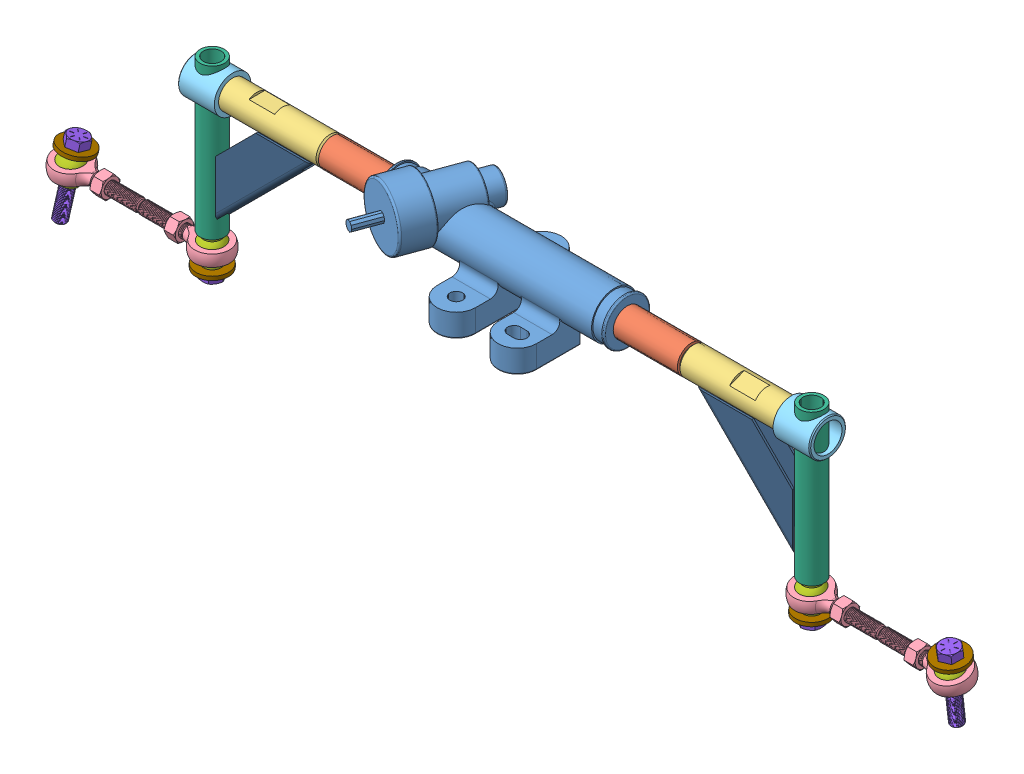
SolidWorks assembly steering assembly, configuration Default. Lengths in mm.
Overall size (719.66 185.7 106.9).
27 component instances, 11 part files, 77 mates.
Components (placement in the parent):
- prebuilt housing-1: prebuilt housing [Default] at (-22.0598 82.7728 134.0833) size (180 70.59 106.9)
- prebuilt rack-1: prebuilt rack [Default] at (207.9402 82.7728 134.0833) x (0 0.567124 0.823632) z (0 -0.823632 0.567124) size (22 312 22)
- extender-1: extender [Default] at (291.9402 82.7728 134.0833) x (0 0.924347 0.381554) z (0 -0.381554 0.924347) size (21.8 84.01 21.8)
- extender-2: extender [Default] at (-156.0598 82.7728 134.0833) x (0 -0.999985 -0.005515) z (0 -0.005515 0.999985) size (21.8 84.01 21.8)
- 3-8-24 swivel-2: 3-8-24 swivel [Default] at (-221.5288 30.3182 118.8367) x (0 -0.06645 0.99779) z (0 -0.99779 -0.06645) size (28.57 68.61 16.22)
- 3-8-24 swivel-3: 3-8-24 swivel [Default] at (-219.9278 28.9769 153.7657) x (0 0.010267 -0.999947) z (0 -0.999947 -0.010267) size (28.57 68.61 16.22)
- 3-8-24 swivel-4: 3-8-24 swivel [Default] at (355.8083 30.5302 119.6738) x (0 -0.080712 0.996738) z (0 -0.996738 -0.080712) size (28.57 68.61 16.22)
- 3-8-24 swivel-5: 3-8-24 swivel [Default] at (357.4092 22.1199 167.5981) x (0 0.263498 -0.96466) z (0 -0.96466 -0.263498) size (28.57 68.61 16.22)
- RackVertAdapt-1: RackVertAdapt [Default] at (-178.6598 82.7728 134.0833) size (28.57 28.57 28.57)
- RackVertAdapt-2: RackVertAdapt [Default] at (314.5402 82.7728 134.0833) x (-1 0 0) z (0 0 -1) size (28.57 28.57 28.57)
- Rackvertical-1: Rackvertical [Default] at (-165.9598 -16.996 134.0833) size (19.05 117.47 19.05)
- Rackvertical-2: Rackvertical [Default] at (301.8402 -16.996 134.0833) x (-0.951218 0 -0.308519) z (0.308519 0 -0.951218) size (19.05 117.47 19.05)
- BallSuper-Swivel  Joint Rod End6960T231_-1: BallSuper-Swivel  Joint Rod End6960T231_ [6960T231] at (-156.8566 -28.1085 117.349) x (0.878438 0 0.477856) z (0 -1 0) size (20.64 20.64 22.23)
- BallSuper-Swivel  Joint Rod End6960T231_-2: BallSuper-Swivel  Joint Rod End6960T231_ [6960T231] at (319.6786 -28.1085 127.398) x (0.350934 0 0.9364) z (0 -1 0) size (20.64 20.64 22.23)
- BallSuper-Swivel  Joint Rod End6960T231_-4: BallSuper-Swivel  Joint Rod End6960T231_ [6960T231] at (393.3175 -26.7315 128.1798) x (0.316739 0.120745 -0.940796) z (-0.030588 -0.990048 -0.137364) size (20.64 20.64 22.23)
- 91257A659_Zinc Yellow-Chromate Plated Hex Head Screw-2: 91257A659_Zinc Yellow-Chromate Plated Hex Head Screw [91257A659] at (411.1286 -36.1556 132.9668) x (-0.030588 -0.990048 -0.137364) z (-0.987463 0.051224 -0.14931) size (57.6 16.5 14.29)
- 91257A659_Zinc Yellow-Chromate Plated Hex Head Screw-3: 91257A659_Zinc Yellow-Chromate Plated Hex Head Screw [91257A659] at (301.8402 -19.9805 134.0833) x (0 1 0) z (-0.546944 0 0.837169) size (57.6 16.5 14.29)
- 91257A659_Zinc Yellow-Chromate Plated Hex Head Screw-4: 91257A659_Zinc Yellow-Chromate Plated Hex Head Screw [91257A659] at (-165.9598 -19.9805 134.0833) x (0 1 0) z (0 0 1) size (57.6 16.5 14.29)
- 3-8 98029A046_Black-Oxide Steel Oversized Washer-2: 3-8 98029A046_Black-Oxide Steel Oversized Washer [98029A046] at (-165.9598 -40.7133 134.0833) x (0.990245 0 -0.139337) z (0 1 0) size (25.4 25.4 2.98)
- 3-8 98029A046_Black-Oxide Steel Oversized Washer-3: 3-8 98029A046_Black-Oxide Steel Oversized Washer [98029A046] at (301.8402 -40.7133 134.0833) x (1 0 0) z (0 1 0) size (25.4 25.4 2.98)
- 3-8 98029A046_Black-Oxide Steel Oversized Washer-4: 3-8 98029A046_Black-Oxide Steel Oversized Washer [98029A046] at (411.7628 -15.6292 135.8147) x (-0.655719 -0.083846 0.750335) z (0.030588 0.990048 0.137364) size (25.4 25.4 2.98)
- BallSuper-Swivel  Joint Rod End6960T231_-5: BallSuper-Swivel  Joint Rod End6960T231_ [6960T231] at (-293.2915 -25.3278 140.2896) x (-0.34361 -0.120036 -0.93141) z (-0.096851 -0.98198 0.162283) size (20.64 20.64 22.23)
- 3-8 98029A046_Black-Oxide Steel Oversized Washer-5: 3-8 98029A046_Black-Oxide Steel Oversized Washer [98029A046] at (-274.276 -15.7309 132.0377) x (0.995265 -0.096906 0.007598) z (-0.096851 -0.98198 0.162283) size (25.4 25.4 2.98)
- 91257A659_Zinc Yellow-Chromate Plated Hex Head Screw-5: 91257A659_Zinc Yellow-Chromate Plated Hex Head Screw [91257A659] at (-276.284 -36.09 135.4023) x (-0.096851 -0.98198 0.162283) z (-0.622443 0.186989 0.76) size (57.6 16.5 14.29)
- Part1^steering assembly-1: Part1^steering assembly [Default] at origin (virtual)
- GussetSteering-2: GussetSteering [Default] at (130.9725 -5.6175 134.0833) size (74.76 74.76 14.22)
- GussetSteering-3: GussetSteering [Default] at (-78.221 -90.1796 134.0833) x (0 1 0) z (0 0 1) size (74.76 74.76 14.22)
Mates (geometry in assembly coordinates):
- Concentric1: concentric anti-aligned: cylinder of prebuilt housing-1 through (157.9402 82.7728 134.0833) axis (-1 0 0) radius 11; cylinder of prebuilt rack-1 through (-72.0598 82.7728 134.0833) axis (1 0 0) radius 11
- Concentric5: concentric anti-aligned: circle of prebuilt ball joint-1; circle of prebuilt ball joint end-1
- Concentric6: concentric: sphere of prebuilt ball joint end-1; sphere of ball end joint conection piece-1
- Concentric8: concentric anti-aligned: circle of prebuilt rack-1; cylinder of extender-1 through (177.1104 82.7728 134.0833) axis (1 0 0) radius 10.9
- Coincident3: coincident anti-aligned: plane of prebuilt rack-1 through (-72.0598 95.1403 107.9625) normal (-1 0 0); plane of extender-2 through (-72.0598 99.5437 110.5464) normal (1 0 0)
- Coincident8: coincident anti-aligned: plane of prebuilt rack-1 through (207.9402 95.1403 107.9625) normal (1 0 0); circle of extender-1
- Coincident4: coincident anti-aligned: plane of prebuilt rack-1 through (207.9402 95.1403 107.9625) normal (1 0 0); plane of extender-1 through (207.9402 76.4066 105.8925) normal (-1 0 0)
- Concentric10: concentric anti-aligned: circle of extender-2; circle of rackBallEnd-2
- Coincident5: coincident anti-aligned: plane of extender-2 through (-156.0598 82.7728 134.0833) normal (-1 0 0); plane of rackBallEnd-2 through (-137.0598 82.7728 134.0833) normal (1 0 0)
- Concentric11: concentric anti-aligned: circle of extender-1; circle of rackBallEnd-1
- Coincident6: coincident anti-aligned: plane of extender-1 through (291.9402 82.7728 134.0833) normal (1 0 0); plane of rackBallEnd-1 through (272.9402 82.7728 134.0833) normal (-1 0 0)
- Concentric12: concentric: sphere of prebuilt ball joint-1; sphere of rackBallEnd-1
- Concentric13: concentric: sphere of prebuilt ball joint-2; sphere of rackBallEnd-2
- Coincident7: coincident: point of prebuilt housing-1; point of prebuilt rack-1
- Parallel3: parallel anti-aligned: plane of prebuilt ball joint-1 through (357.8661 84.527 123.1579) normal (0.9847 0.027626 -0.172054); plane of prebuilt ball joint end-1 through (367.9391 84.8096 121.3978) normal (-0.9847 -0.027626 0.172054)
- Lock1: lock: unknown of prebuilt ball joint-1; unknown of prebuilt ball joint end-1
- Concentric14: concentric aligned: cylinder of extender-2 through (-41.2299 82.7728 134.0833) axis (-1 0 0) radius 10.9; cylinder of RackVertAdapt-1 through (-150.0848 82.7728 134.0833) axis (-1 0 0) radius 10.9093
- Concentric15: concentric aligned: cylinder of extender-1 through (177.1104 82.7728 134.0833) axis (1 0 0) radius 10.9; cylinder of RackVertAdapt-2 through (285.9652 82.7728 134.0833) axis (1 0 0) radius 10.9093
- Concentric16: concentric anti-aligned: cylinder of RackVertAdapt-2 through (301.8402 63.7228 134.0833) axis (0 1 0) radius 9.5885
- Concentric17: concentric anti-aligned: cylinder of RackVertAdapt-1 through (-165.9598 63.7228 134.0833) axis (0 1 0) radius 9.5885
- Coincident11: coincident aligned: line of Rackvertical-2 through (301.8402 100.479 134.0833) axis (0 -1 0)
- Coincident12: coincident: point of Rackvertical-2; point of assembly
- Coincident13: coincident aligned: line of Rackvertical-1 through (-165.9598 100.479 134.0833) axis (0 -1 0)
- Coincident14: coincident: point of Rackvertical-1; point of assembly
- Concentric19: concentric anti-aligned: circle of Rackvertical-1; circle of BallSuper-Swivel  Joint Rod End6960T231_-1
- Coincident15: coincident aligned: plane of Rackvertical-1 through (-175.4848 -16.996 134.0833) normal (0 -1 0); circle of BallSuper-Swivel  Joint Rod End6960T231_-1
- Concentric22: concentric anti-aligned: circle of Rackvertical-2; circle of BallSuper-Swivel  Joint Rod End6960T231_-2
- Coincident16: coincident aligned: plane of Rackvertical-2 through (310.9006 -16.996 137.0219) normal (0 -1 0); circle of BallSuper-Swivel  Joint Rod End6960T231_-2
- Concentric23: concentric anti-aligned: circle of BallSuper-Swivel  Joint Rod End6960T231_-1; circle of 3-8 98029A046_Black-Oxide Steel Oversized Washer-2
- Coincident17: coincident anti-aligned: circle of BallSuper-Swivel  Joint Rod End6960T231_-1; plane of 3-8 98029A046_Black-Oxide Steel Oversized Washer-2 through (-165.9598 -39.221 134.0833) normal (0 1 0)
- Concentric25: concentric anti-aligned: circle of BallSuper-Swivel  Joint Rod End6960T231_-2; circle of 3-8 98029A046_Black-Oxide Steel Oversized Washer-3
- Coincident19: coincident anti-aligned: circle of BallSuper-Swivel  Joint Rod End6960T231_-2; plane of 3-8 98029A046_Black-Oxide Steel Oversized Washer-3 through (301.8402 -39.221 134.0833) normal (0 1 0)
- Coincident21: coincident aligned: plane of 91257A659_Zinc Yellow-Chromate Plated Hex Head Screw-3 through (294.4801 -42.2055 137.808) normal (0 1 0); circle of 3-8 98029A046_Black-Oxide Steel Oversized Washer-3
- Coincident22: coincident: point of 3-8-24 swivel-2; point of ?
- Concentric27: concentric anti-aligned: cylinder of BallSuper-Swivel  Joint Rod End6960T231_-3 through (-265.1781 -28.1085 134.0833) axis (-1 0 0) radius 4.7625; cylinder of 91257A659_Zinc Yellow-Chromate Plated Hex Head Screw-1 through (-289.5938 -28.1085 134.0833) axis (1 0 0) radius 4.7625
- Concentric28: concentric anti-aligned: circle of 91257A659_Zinc Yellow-Chromate Plated Hex Head Screw-1; circle of 3-8 98029A046_Black-Oxide Steel Oversized Washer-1
- Coincident23: coincident anti-aligned: plane of BallSuper-Swivel  Joint Rod End6960T231_-3 through (-286.6093 -28.1085 134.0833) normal (-1 0 0); plane of 3-8 98029A046_Black-Oxide Steel Oversized Washer-1 through (-286.6093 -28.1085 134.0833) normal (1 0 0)
- Coincident26: coincident anti-aligned: plane of 91257A659_Zinc Yellow-Chromate Plated Hex Head Screw-1 through (-289.5938 -29.7027 125.9899) normal (1 0 0); plane of 3-8 98029A046_Black-Oxide Steel Oversized Washer-1 through (-289.5938 -28.1085 134.0833) normal (-1 0 0)
- Concentric29: concentric anti-aligned: cylinder of 91257A659_Zinc Yellow-Chromate Plated Hex Head Screw-3 through (301.8402 -42.2055 134.0833) axis (0 1 0) radius 4.7625
- Coincident27: coincident: point of 3-8-24 swivel-4; point of assembly
- Concentric30: concentric anti-aligned: circle of BallSuper-Swivel  Joint Rod End6960T231_-4; circle of 3-8 98029A046_Black-Oxide Steel Oversized Washer-4
- Coincident28: coincident aligned: circle of BallSuper-Swivel  Joint Rod End6960T231_-4; plane of 3-8 98029A046_Black-Oxide Steel Oversized Washer-4 through (411.7172 -17.1066 135.6097) normal (-0.030588 -0.990048 -0.137364)
- Concentric31: concentric aligned: cylinder of 91257A659_Zinc Yellow-Chromate Plated Hex Head Screw-2 through (411.8085 -14.1518 136.0197) axis (-0.030588 -0.990048 -0.137364) radius 4.7625; cylinder of 3-8 98029A046_Black-Oxide Steel Oversized Washer-4 through (411.8085 -14.1518 136.0197) axis (-0.030588 -0.990048 -0.137364) radius 5.1562
- Coincident29: coincident anti-aligned: plane of 91257A659_Zinc Yellow-Chromate Plated Hex Head Screw-2 through (404.1156 -14.3265 138.9917) normal (-0.030588 -0.990048 -0.137364); circle of 3-8 98029A046_Black-Oxide Steel Oversized Washer-4
- Coincident30: coincident: point of BallSuper-Swivel  Joint Rod End6960T231_-4; point of assembly
- Coincident31: coincident: point of 3-8-24 swivel-5; point of assembly
- Concentric32: concentric anti-aligned: cylinder of 91257A659_Zinc Yellow-Chromate Plated Hex Head Screw-4 through (-165.9598 -42.2055 134.0833) axis (0 1 0) radius 4.7625; cylinder of 3-8 98029A046_Black-Oxide Steel Oversized Washer-2 through (-165.9598 -39.221 134.0833) axis (0 -1 0) radius 5.1562
- Coincident34: coincident: moEndPointRef_w of 91257A659_Zinc Yellow-Chromate Plated Hex Head Screw-4; plane of 3-8 98029A046_Black-Oxide Steel Oversized Washer-2 through (-165.9598 -42.2055 134.0833) normal (0 -1 0)
- Coincident35: coincident: point of 3-8-24 swivel-3; point of assembly
- Coincident36: coincident: point of 3-8-24 swivel-2; point of assembly
- Coincident37: coincident anti-aligned: axis of 3-8-24 swivel-3 through (-158.0573 -28.1085 134.0833) axis (-1 0 0); line of 91257A659_Zinc Yellow-Chromate Plated Hex Head Screw-1 through (-266.9147 -28.1085 134.0833) axis (1 0 0)
- Coincident38: coincident aligned: line of 3-8-24 swivel-2 through (-222.4751 -28.1085 134.0833) axis (-1 0 0); line of 3-8-24 swivel-3 through (-178.2236 -28.1085 134.0833) axis (-1 0 0)
- Coincident39: coincident: point of BallSuper-Swivel  Joint Rod End6960T231_-5; point of assembly
- Concentric33: concentric aligned: circle of BallSuper-Swivel  Joint Rod End6960T231_-5; circle of 3-8 98029A046_Black-Oxide Steel Oversized Washer-5
- Coincident40: coincident anti-aligned: plane of BallSuper-Swivel  Joint Rod End6960T231_-5 through (-274.4206 -17.1963 132.2799) normal (0.096851 0.98198 -0.162283); circle of 3-8 98029A046_Black-Oxide Steel Oversized Washer-5
- Concentric34: concentric anti-aligned: cylinder of 3-8 98029A046_Black-Oxide Steel Oversized Washer-5 through (-274.4206 -17.1963 132.2799) axis (0.096851 0.98198 -0.162283) radius 5.1562; cylinder of 91257A659_Zinc Yellow-Chromate Plated Hex Head Screw-5 through (-274.1315 -14.2656 131.7956) axis (-0.096851 -0.98198 0.162283) radius 4.7625
- Coincident41: coincident aligned: circle of 3-8 98029A046_Black-Oxide Steel Oversized Washer-5; plane of 91257A659_Zinc Yellow-Chromate Plated Hex Head Screw-5 through (-275.3749 -12.8167 139.8205) normal (-0.096851 -0.98198 0.162283)
- Coincident42: coincident anti-aligned: line of 3-8-24 swivel-4 through (354.8619 -28.1085 134.0833) axis (-1 0 0); line of 3-8-24 swivel-5 through (358.3555 -28.1085 134.0833) axis (1 0 0)
- Lock2: lock: unknown of prebuilt rack-1; unknown of extender-2
- Lock3: lock: unknown of extender-2; unknown of RackVertAdapt-1
- Lock4: lock: unknown of RackVertAdapt-1; unknown of Rackvertical-1
- Lock5: lock: unknown of Rackvertical-1; unknown of BallSuper-Swivel  Joint Rod End6960T231_-1
- Lock6: lock: unknown of prebuilt rack-1; unknown of extender-1
- Lock7: lock: unknown of extender-1; unknown of RackVertAdapt-2
- Lock8: lock: unknown of RackVertAdapt-2; unknown of Rackvertical-2
- Lock9: lock: unknown of Rackvertical-2; unknown of BallSuper-Swivel  Joint Rod End6960T231_-2
- Lock10: lock: unknown of 3-8-24 swivel-4; unknown of 3-8-24 swivel-5
- Lock11: lock: unknown of 3-8-24 swivel-2; unknown of 3-8-24 swivel-3
- InPlace1: in place: plane of ? through (-165.9598 0 0) normal (-1 0 0); moOrthogonalPlaneRef_w of ? through (-165.9598 0 0) normal (0 0 1); plane of ? through (-165.9598 0 0) normal (0 -1 0); unknown of ?
- Coincident43: coincident aligned: 
- Coincident44: coincident aligned: plane of Part2^steering assembly-1 through (0 0 134.0833) normal (0 1 0)
- Coincident45: coincident anti-aligned: plane of Part2^steering assembly-1 through (0 0 134.0833) normal (-1 0 0)
- Coincident47: coincident aligned: plane of GussetSteering-1 through (0 0 141.1953) normal (0 0 1); plane of GussetSteering-2 through (130.9725 -5.6175 141.1953) normal (0 0 1)
- Lock12: lock: unknown of extender-1; unknown of GussetSteering-2
- Coincident48: coincident: plane of GussetSteering-2 through (130.9725 -5.6175 141.1953) normal (0 0 1); plane of GussetSteering-3 through (-78.221 -90.1796 141.1953) normal (0 0 1)
- Coincident50: coincident: line of GussetSteering-2 through (262.1898 72.6052 141.1953) axis (-1 0 0); line of GussetSteering-3 through (-86.1737 72.6052 141.1953) axis (-1 0 0)
- Lock13: lock: unknown of extender-2; unknown of GussetSteering-3
